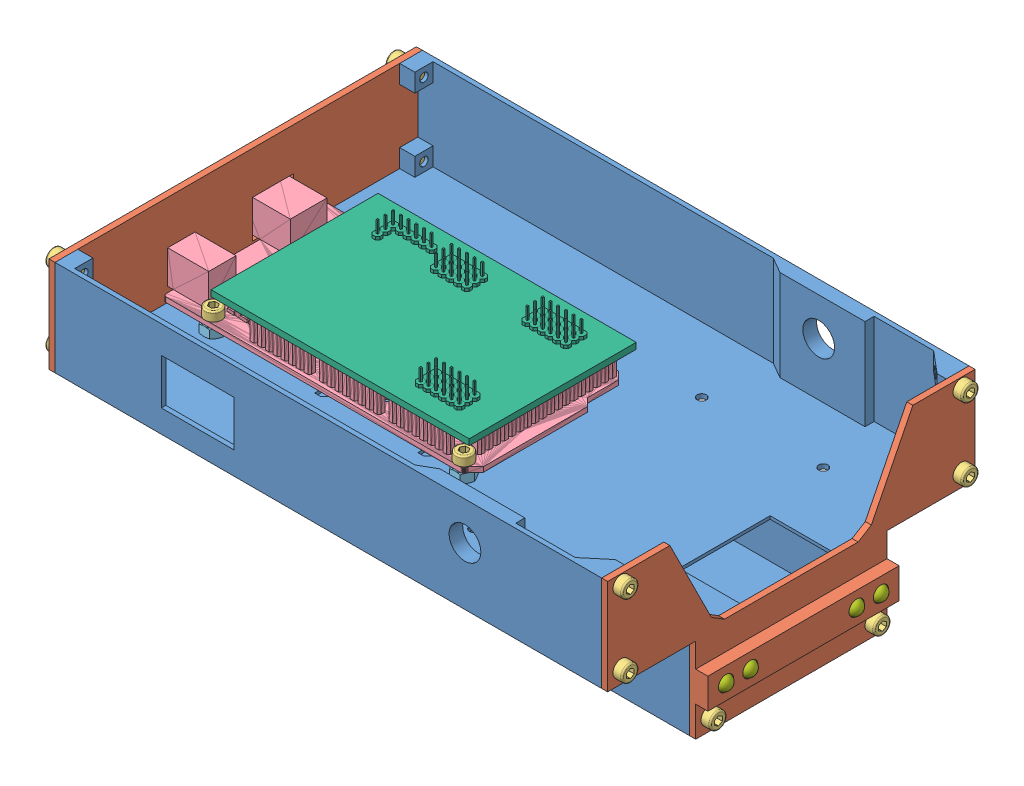
SolidWorks assembly main body, configuration základní. Lengths in mm.
Overall size (195.2 63.55 121).
32 component instances, 8 part files, 56 mates.
Components (placement in the parent):
- body-1: body [Výchozí] at origin size (180 59.5 121)
- BACK PLATE-1: BACK PLATE [back] at (-2 -1.5 0) x (0 0 -1) z (1 0 0) size (121 59.5 6)
- ŠROUB M3 x 12 až 150 DIN 912 A2-1: ŠROUB M3 x 12 až 150 DIN 912 A2 [M3x6] at (-2 55 -56) x (0 1 0) z (-1 0 0) size (8.52 5.5 9)
- ŠROUB M3 x 12 až 150 DIN 912 A2-7: ŠROUB M3 x 12 až 150 DIN 912 A2 [M3x6] at (-2 31 -56) x (0 1 0) z (-1 0 0) size (8.52 5.5 9)
- ŠROUB M3 x 12 až 150 DIN 912 A2-8: ŠROUB M3 x 12 až 150 DIN 912 A2 [M3x6] at (-2 3 -27) x (0 1 0) z (-1 0 0) size (8.52 5.5 9)
- ŠROUB M3 x 12 až 150 DIN 912 A2-9: ŠROUB M3 x 12 až 150 DIN 912 A2 [M3x6] at (-2 3 27) x (0 1 0) z (-1 0 0) size (8.52 5.5 9)
- ŠROUB M3 x 12 až 150 DIN 912 A2-10: ŠROUB M3 x 12 až 150 DIN 912 A2 [M3x6] at (-2 31 56) x (0 1 0) z (-1 0 0) size (8.52 5.5 9)
- ŠROUB M3 x 12 až 150 DIN 912 A2-11: ŠROUB M3 x 12 až 150 DIN 912 A2 [M3x6] at (-2 55 56) x (0 1 0) z (-1 0 0) size (8.52 5.5 9)
- ŠROUB M3 x 12 až 150 DIN 912 A2-16: ŠROUB M3 x 12 až 150 DIN 912 A2 [M3x6] at (182 55 -56) x (0 -1 0) z (1 0 0) size (8.52 5.5 9)
- ŠROUB M3 x 12 až 150 DIN 912 A2-17: ŠROUB M3 x 12 až 150 DIN 912 A2 [M3x6] at (182 31 -56) x (0 -1 0) z (1 0 0) size (8.52 5.5 9)
- ŠROUB M3 x 12 až 150 DIN 912 A2-18: ŠROUB M3 x 12 až 150 DIN 912 A2 [M3x6] at (182 3 -27) x (0 -1 0) z (1 0 0) size (8.52 5.5 9)
- ŠROUB M3 x 12 až 150 DIN 912 A2-19: ŠROUB M3 x 12 až 150 DIN 912 A2 [M3x6] at (182 3 27) x (0 -1 0) z (1 0 0) size (8.52 5.5 9)
- ŠROUB M3 x 12 až 150 DIN 912 A2-20: ŠROUB M3 x 12 až 150 DIN 912 A2 [M3x6] at (182 31 56) x (0 -1 0) z (1 0 0) size (8.52 5.5 9)
- ŠROUB M3 x 12 až 150 DIN 912 A2-21: ŠROUB M3 x 12 až 150 DIN 912 A2 [M3x6] at (182 55 56) x (0 -1 0) z (1 0 0) size (8.52 5.5 9)
- ARDUUINO ASSEMLBY-1: ARDUUINO ASSEMLBY [základní] at (1.8 32.6 26.67) x (0 0 1) z (-1 0 0) size (56.13 25.3 108.63)
  - Arduino_MEGA2560-1: Arduino_MEGA2560 [zakladni] x (0 0 -1) z (0 1 0) size (107.94 53.34 12.6)
  - MATICE M3 DIN 934_POZINK-2: MATICE M3 DIN 934_POZINK [Hexagon Nut ISO 4032 - M6 - D - C] at (-2.54 -1.6 -96.52) x (0.5 0 0.866025) z (0 1 0) size (6 6.93 3)
  - ŠROUB M3 x 12 až 150 DIN 912 A2-2: ŠROUB M3 x 12 až 150 DIN 912 A2 [M3x10] at (-2.54 0 -96.52) x (0 0 1) z (0 1 0) size (8.52 5.5 13)
  - MATICE M3 DIN 934_POZINK-3: MATICE M3 DIN 934_POZINK [Hexagon Nut ISO 4032 - M6 - D - C] at (-2.543 -1.6 -13.9775) x (1 0 0) z (0 1 0) size (6 6.93 3)
  - ŠROUB M3 x 12 až 150 DIN 912 A2-3: ŠROUB M3 x 12 až 150 DIN 912 A2 [M3x10] at (-2.543 0 -13.9775) x (0.866025 0 0.5) z (0 1 0) size (8.52 5.5 13)
  - shield-1: shield [Výchozí] at (-26.67 8.3 -59.0999) size (55 7 85)
- BACK PLATE-3: BACK PLATE [front] at (182 -1.5 0) x (0 0 1) z (-1 0 0) size (121 59.5 6)
- led_white-1: led_white [Výchozí] at (179 13.5 25.5) x (0 0 -1) z (0 -1 0) size (5.5 8.6 6)
- led_white-2: led_white [Výchozí] at (179 13.5 17.5) x (0 0 -1) z (0 -1 0) size (5.5 8.6 6)
- led_white-3: led_white [Výchozí] at (179 13.5 -17.5) x (0 0 -1) z (0 -1 0) size (5.5 8.6 6)
- led_white-4: led_white [Výchozí] at (179 13.5 -25.5) x (0 0 -1) z (0 -1 0) size (5.5 8.6 6)
- led_red-1: led_red [Výchozí] at (1 13.5 -25.5) x (0 0 1) z (0 -1 0) size (5.5 8.6 6)
- led_red-2: led_red [Výchozí] at (1 13.5 -17.5) x (0 0 1) z (0 -1 0) size (5.5 8.6 6)
- led_red-3: led_red [Výchozí] at (1 13.5 17.5) x (0 0 1) z (0 -1 0) size (5.5 8.6 6)
- led_red-4: led_red [Výchozí] at (1 13.5 25.5) x (0 0 1) z (0 -1 0) size (5.5 8.6 6)
- MATICE M3 DIN 934_POZINK-1: MATICE M3 DIN 934_POZINK [Hexagon Nut ISO 4032 - M6 - D - C] at (6.3 24 -28.6112) x (1 0 0) z (0 -1 0) size (6 6.93 3)
- MATICE M3 DIN 934_POZINK-2: MATICE M3 DIN 934_POZINK [Hexagon Nut ISO 4032 - M6 - D - C] at (88.8425 24 -28.6082) x (0 0 -1) z (0 -1 0) size (6 6.93 3)
Mates (geometry in assembly coordinates):
- Sjednocená1: coincident anti-aligned: plane of body-1 through (0 0 0) normal (-1 0 0); plane of BACK PLATE-1 through (0 -1.5 0) normal (1 0 0)
- Sjednocená2: coincident: line of body-1 through (0 58 53) axis (0 0 1); plane of BACK PLATE-1 through (0 58 -60.5) normal (0 1 0)
- Sjednocená3: coincident anti-aligned: plane of BACK PLATE-1 through (-2 -1.5 0) normal (0 0 -1); plane of assembly through (0 0 0) normal (0 0 1)
- Soustředná1: concentric aligned: cylinder of body-1 through (5 55 -56) axis (-1 0 0) radius 1.4; cylinder of ŠROUB M3 x 12 až 150 DIN 912 A2-1 through (4 55 -56) axis (-1 0 0) radius 1.5
- Sjednocená4: coincident anti-aligned: plane of BACK PLATE-1 through (-2 -1.5 0) normal (-1 0 0); plane of ŠROUB M3 x 12 až 150 DIN 912 A2-1 through (-2 55 -56) normal (1 0 0)
- Rovnoběžná1: parallel aligned: plane of BACK PLATE-1 through (0 26.5 -60.5) normal (0 0 -1); plane of ŠROUB M3 x 12 až 150 DIN 912 A2-1 through (-3 54.2783 -54.75) normal (0 0 -1)
- Sjednocená5: coincident anti-aligned: plane of BACK PLATE-1 through (-2 -1.5 0) normal (-1 0 0); plane of ŠROUB M3 x 12 až 150 DIN 912 A2-7 through (-2 31 -56) normal (1 0 0)
- Rovnoběžná2: parallel aligned: plane of BACK PLATE-1 through (0 26.5 -60.5) normal (0 0 -1); plane of ŠROUB M3 x 12 až 150 DIN 912 A2-7 through (-3 30.2783 -54.75) normal (0 0 -1)
- Soustředná2: concentric aligned: cylinder of BACK PLATE-1 through (8 31 -56) axis (-1 0 0) radius 1.75; cylinder of ŠROUB M3 x 12 až 150 DIN 912 A2-7 through (4 31 -56) axis (-1 0 0) radius 1.5
- Soustředná3: concentric aligned: cylinder of BACK PLATE-1 through (8 3 -27) axis (-1 0 0) radius 1.75; cylinder of ŠROUB M3 x 12 až 150 DIN 912 A2-8 through (4 3 -27) axis (-1 0 0) radius 1.5
- Sjednocená6: coincident anti-aligned: plane of BACK PLATE-1 through (-2 -1.5 0) normal (-1 0 0); plane of ŠROUB M3 x 12 až 150 DIN 912 A2-8 through (-2 3 -27) normal (1 0 0)
- Rovnoběžná3: parallel aligned: plane of BACK PLATE-1 through (0 26.5 -60.5) normal (0 0 -1); plane of ŠROUB M3 x 12 až 150 DIN 912 A2-8 through (-3 2.2783 -25.75) normal (0 0 -1)
- Soustředná4: concentric aligned: circle of BACK PLATE-1; cylinder of ŠROUB M3 x 12 až 150 DIN 912 A2-9 through (4 3 27) axis (-1 0 0) radius 1.5
- Sjednocená7: coincident anti-aligned: plane of BACK PLATE-1 through (-2 -1.5 0) normal (-1 0 0); plane of ŠROUB M3 x 12 až 150 DIN 912 A2-9 through (-2 3 27) normal (1 0 0)
- Rovnoběžná4: parallel aligned: plane of BACK PLATE-1 through (0 26.5 -60.5) normal (0 0 -1); plane of ŠROUB M3 x 12 až 150 DIN 912 A2-9 through (-3 2.2783 28.25) normal (0 0 -1)
- Soustředná5: concentric aligned: circle of BACK PLATE-1; cylinder of ŠROUB M3 x 12 až 150 DIN 912 A2-10 through (4 31 56) axis (-1 0 0) radius 1.5
- Sjednocená8: coincident anti-aligned: plane of BACK PLATE-1 through (-2 -1.5 0) normal (-1 0 0); plane of ŠROUB M3 x 12 až 150 DIN 912 A2-10 through (-2 31 56) normal (1 0 0)
- Rovnoběžná5: parallel aligned: plane of BACK PLATE-1 through (0 26.5 -60.5) normal (0 0 -1); plane of ŠROUB M3 x 12 až 150 DIN 912 A2-10 through (-3 30.2783 57.25) normal (0 0 -1)
- Soustředná6: concentric aligned: cylinder of BACK PLATE-1 through (8 55 56) axis (-1 0 0) radius 1.75; cylinder of ŠROUB M3 x 12 až 150 DIN 912 A2-11 through (4 55 56) axis (-1 0 0) radius 1.5
- Sjednocená9: coincident anti-aligned: plane of BACK PLATE-1 through (-2 -1.5 0) normal (-1 0 0); plane of ŠROUB M3 x 12 až 150 DIN 912 A2-11 through (-2 55 56) normal (1 0 0)
- Rovnoběžná6: parallel aligned: plane of BACK PLATE-1 through (0 26.5 -60.5) normal (0 0 -1); plane of ŠROUB M3 x 12 až 150 DIN 912 A2-11 through (-3 54.2783 57.25) normal (0 0 -1)
- Rovnoběžná29: parallel anti-aligned: plane of body-1 through (180 28 -60.5) normal (0 0 -1); plane of ARDUUINO ASSEMLBY-1/Arduino_MEGA2560-1 through (1.8 32.6 26.67) normal (0 0 1)
- Sjednocená122: coincident anti-aligned: plane of body-1 through (180 0 0) normal (1 0 0); plane of BACK PLATE-3 through (180 -1.5 0) normal (-1 0 0)
- Soustředná40: concentric aligned: circle of ŠROUB M3 x 12 až 150 DIN 912 A2-16; circle of BACK PLATE-3
- Soustředná41: concentric anti-aligned: circle of ŠROUB M3 x 12 až 150 DIN 912 A2-21; circle of BACK PLATE-3
- Soustředná42: concentric anti-aligned: cylinder of BACK PLATE-3 through (162 13.5 25.5) axis (1 0 0) radius 2.5; cylinder of led_white-1 through (179 13.5 25.5) axis (-1 0 0) radius 2.5
- Sjednocená123: coincident aligned: circle of BACK PLATE-3; plane of led_white-1 through (180 13.5 28.5) normal (1 0 0)
- Rovnoběžná30: parallel: plane of body-1 through (180 0 30) normal (0 0 -1); line of led_white-1 through (179 15.1583 23) axis (0 -1 0)
- Sjednocená125: coincident aligned: circle of BACK PLATE-3; plane of led_white-2 through (180 13.5 20.5) normal (1 0 0)
- Rovnoběžná31: parallel: plane of body-1 through (180 0 30) normal (0 0 -1); line of led_white-2 through (179 15.1583 15) axis (0 -1 0)
- Soustředná43: concentric anti-aligned: cylinder of BACK PLATE-3 through (162 13.5 17.5) axis (1 0 0) radius 2.5; cylinder of led_white-2 through (179 13.5 17.5) axis (-1 0 0) radius 2.5
- Soustředná44: concentric anti-aligned: cylinder of BACK PLATE-3 through (162 13.5 -17.5) axis (1 0 0) radius 2.5; cylinder of led_white-3 through (179 13.5 -17.5) axis (-1 0 0) radius 2.5
- Sjednocená126: coincident aligned: circle of BACK PLATE-3; plane of led_white-3 through (180 13.5 -14.5) normal (1 0 0)
- Rovnoběžná32: parallel: plane of body-1 through (180 0 30) normal (0 0 -1); line of led_white-3 through (179 15.1583 -20) axis (0 -1 0)
- Soustředná45: concentric anti-aligned: cylinder of BACK PLATE-3 through (162 13.5 -25.5) axis (1 0 0) radius 2.5; cylinder of led_white-4 through (179 13.5 -25.5) axis (-1 0 0) radius 2.5
- Sjednocená127: coincident aligned: circle of BACK PLATE-3; plane of led_white-4 through (180 13.5 -22.5) normal (1 0 0)
- Rovnoběžná33: parallel: plane of body-1 through (180 0 30) normal (0 0 -1); line of led_white-4 through (179 15.1583 -28) axis (0 -1 0)
- Soustředná46: concentric anti-aligned: cylinder of BACK PLATE-1 through (18 13.5 -25.5) axis (-1 0 0) radius 2.5; cylinder of led_red-1 through (1 13.5 -25.5) axis (1 0 0) radius 2.5
- Sjednocená128: coincident aligned: circle of BACK PLATE-1; plane of led_red-1 through (0 13.5 -28.5) normal (-1 0 0)
- Kolmá1: perpendicular: line of BACK PLATE-1 through (-6 18.5 -31.5) axis (0 0 1); line of led_red-1 through (1 15.1583 -23) axis (0 -1 0)
- Sjednocená130: coincident aligned: circle of BACK PLATE-1; plane of led_red-2 through (0 13.5 -20.5) normal (-1 0 0)
- Kolmá2: perpendicular: line of BACK PLATE-1 through (-6 18.5 -31.5) axis (0 0 1); line of led_red-2 through (1 15.1583 -15) axis (0 -1 0)
- Soustředná47: concentric anti-aligned: cylinder of BACK PLATE-1 through (18 13.5 -17.5) axis (-1 0 0) radius 2.5; cylinder of led_red-2 through (1 13.5 -17.5) axis (1 0 0) radius 2.5
- Soustředná48: concentric anti-aligned: cylinder of BACK PLATE-1 through (18 13.5 17.5) axis (-1 0 0) radius 2.5; cylinder of led_red-3 through (1 13.5 17.5) axis (1 0 0) radius 2.5
- Sjednocená131: coincident aligned: circle of BACK PLATE-1; plane of led_red-3 through (0 13.5 14.5) normal (-1 0 0)
- Kolmá3: perpendicular: line of BACK PLATE-1 through (-6 18.5 -31.5) axis (0 0 1); line of led_red-3 through (1 15.1583 20) axis (0 -1 0)
- Soustředná49: concentric anti-aligned: cylinder of BACK PLATE-1 through (18 13.5 25.5) axis (-1 0 0) radius 2.5; cylinder of led_red-4 through (1 13.5 25.5) axis (1 0 0) radius 2.5
- Sjednocená132: coincident aligned: circle of BACK PLATE-1; plane of led_red-4 through (0 13.5 22.5) normal (-1 0 0)
- Kolmá4: perpendicular: line of BACK PLATE-1 through (-6 18.5 -31.5) axis (0 0 1); line of led_red-4 through (1 15.1583 28) axis (0 -1 0)
- Sjednocená133: coincident anti-aligned: plane of body-1 through (240.0083 27 -30) normal (0 -1 0); plane of MATICE M3 DIN 934_POZINK-1 through (6.3 27 -25.1471) normal (0 1 0)
- Rovnoběžná35: parallel aligned: plane of BACK PLATE-1 through (0 -1.5 0) normal (1 0 0); plane of MATICE M3 DIN 934_POZINK-1 through (9.3 27 -26.8792) normal (1 0 0)
- Sjednocená136: coincident aligned: plane of MATICE M3 DIN 934_POZINK-1 through (6.3 24 -25.1471) normal (0 -1 0); plane of MATICE M3 DIN 934_POZINK-2 through (92.3066 24 -28.6082) normal (0 -1 0)
- Rovnoběžná38: parallel aligned: plane of body-1 through (180 28 -30) normal (0 1 0); plane of ARDUUINO ASSEMLBY-1/Arduino_MEGA2560-1 through (1.8 43.6 26.67) normal (0 1 0)
- Sjednocená140: coincident anti-aligned: plane of body-1 through (180 28 -30) normal (0 1 0); plane of ARDUUINO ASSEMLBY-1/MATICE M3 DIN 934_POZINK-2 through (100.052 28 27.13) normal (0 -1 0)
- Sjednocená141: coincident anti-aligned: plane of BACK PLATE-1 through (0 -1.5 0) normal (1 0 0); plane of ARDUUINO ASSEMLBY-1/Arduino_MEGA2560-1 through (0 32.6 26.67) normal (-1 0 0)
- Vystředění1: width aligned: plane of body-1 through (180 28 59) normal (0 0 -1); plane of body-1 through (180 28 -59) normal (0 0 1); plane of ARDUUINO ASSEMLBY-1/Arduino_MEGA2560-1 through (1.8 32.6 -25.4) normal (0 0 -1); plane of ARDUUINO ASSEMLBY-1/Arduino_MEGA2560-1 through (1.8 32.6 25.4) normal (0 0 1)
